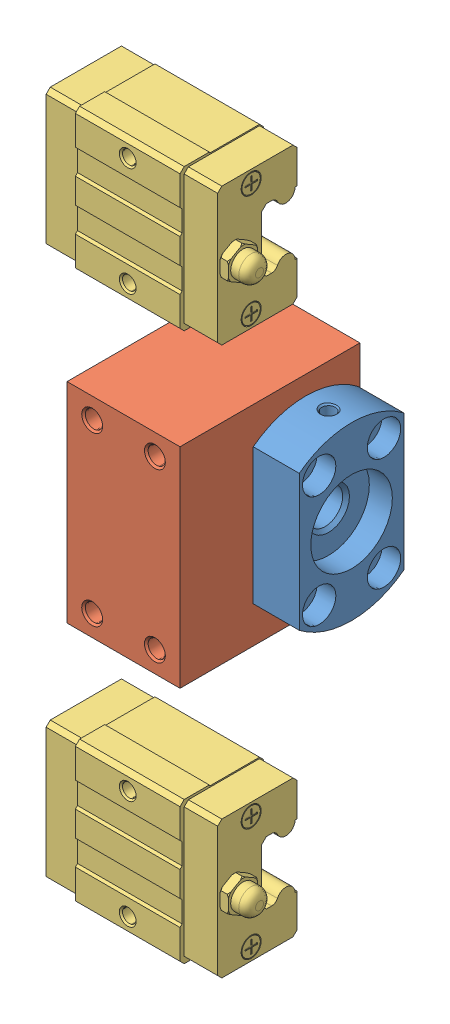
SolidWorks assembly Schlitten.Z.Achse, configuration Standard. Lengths in mm.
Overall size (47 165 43).
4 component instances, 3 part files, 9 mates.
Components (placement in the parent):
- 2-1: 2 [Standard] at (-122.3778 0.5398 41) size (31 41 25)
- bnfb1004c_30_2_14b-1: bnfb1004c_30_2_14b [Standard] at (-9.3778 0.5398 41) x (0 1 0) z (1 0 0) size (50 43 27)
- 2.1.1.1-1: 2.1.1.1 [Standard] at (-8.3778 66.0398 47) x (0 1 0) z (1 0 0) size (34 20 47)
- 2.1.1.1-2: 2.1.1.1 [Standard] at (-8.3778 -64.9602 47) x (0 1 0) z (1 0 0) size (34 20 47)
Mates (geometry in assembly coordinates):
- Deckungsgleich1: coincident anti-aligned: plane of 2-1 through (4.1222 0.5398 41) normal (-1 0 0); plane of bnfb1004c_30_2_14b-1 through (4.1222 0.5398 41) normal (1 0 0)
- Konzentrisch1: concentric aligned: cylinder of 2-1 through (-5.6278 0.5398 41) axis (1 0 0) radius 11.5; cylinder of bnfb1004c_30_2_14b-1 through (4.1222 0.5398 41) axis (1 0 0) radius 11.2
- Parallel1: parallel aligned: plane of 2-1 through (4.1222 -15.7083 53.5) normal (0 0 1); plane of bnfb1004c_30_2_14b-1 through (4.1222 25.5398 71) normal (0 0 1)
- Abstand4: distance = 6 mm aligned: plane of bnfb1004c_30_2_14b-1 through (-22.8778 0.5398 41) normal (-1 0 0); plane of 2.1.1.1-2 through (-28.8778 -64.9602 51) normal (-1 0 0)
- Deckungsgleich4: coincident aligned: plane of bnfb1004c_30_2_14b-1 through (4.1222 25.5398 71) normal (0 0 1); plane of 2.1.1.1-1 through (10.1222 69.0398 71) normal (0 0 1)
- Abstand1: distance = 23.5 mm anti-aligned: plane of 2.1.1.1-1 through (10.1222 49.0398 70) normal (0 -1 0); plane of bnfb1004c_30_2_14b-1 through (4.1222 25.5398 28) normal (0 1 0)
- Abstand3: distance = 6 mm aligned: plane of bnfb1004c_30_2_14b-1 through (-22.8778 0.5398 41) normal (-1 0 0); plane of 2.1.1.1-1 through (-28.8778 66.0398 51) normal (-1 0 0)
- Deckungsgleich8: coincident: plane of bnfb1004c_30_2_14b-1 through (4.1222 25.5398 71) normal (0 0 1); plane of 2.1.1.1-2 through (10.1222 -61.9602 71) normal (0 0 1)
- Abstand2: distance = 23.5 mm anti-aligned: plane of 2.1.1.1-2 through (10.1222 -47.9602 64) normal (0 1 0); plane of bnfb1004c_30_2_14b-1 through (4.1222 -24.4602 71) normal (0 -1 0)
